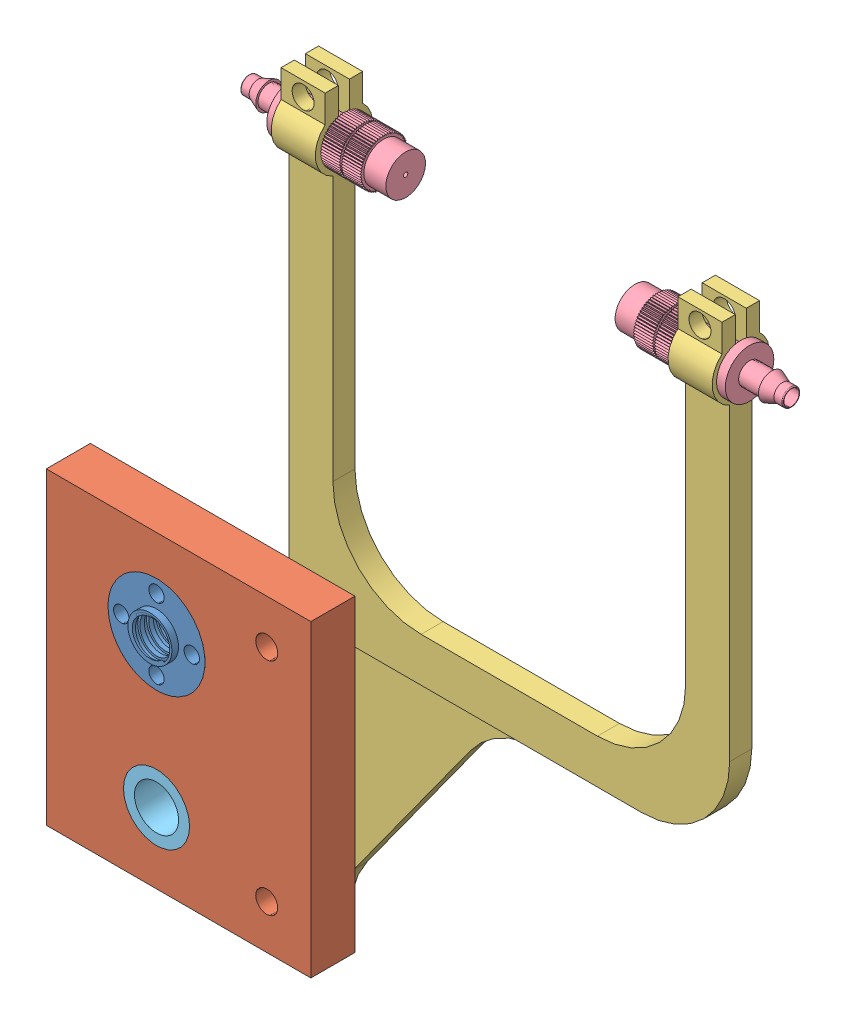
SolidWorks assembly rinser, configuration Default. Lengths in mm.
Overall size (156.5 167.17 22.24).
6 component instances, 5 part files, 11 mates.
Components (placement in the parent):
- 8mm slider-1: 8mm slider [Default] at (33.5116 -43.1967 -70.809) size (22 22 16.69)
- bearing block-1: bearing block [Default] at (33.5116 -43.1967 -77.809) size (60 70 10)
- nozzle holder-1: nozzle holder [Default] at (42.1087 -41.0385 -77.809) x (-1 0 0) z (0 0 -1) size (100 167.17 13)
- nozzle-1: nozzle [Default] at (37.0116 77.8033 -80.309) x (0 -0.928234 -0.371996) z (1 0 0) size (11 11 35.5)
- nozzle-2: nozzle [Default] at (160.0116 77.8033 -80.309) x (0 0.00294 0.999996) z (-1 0 0) size (11 11 35.5)
- linear slider-1: linear slider [Default] at (28.5116 -62.1967 -77.809) size (15 15 10)
Mates (geometry in assembly coordinates):
- Concentric1: concentric: cylinder of 8mm slider-1 through (28.5116 -28.1967 -67.809) axis (0 0 -1) radius 11; cylinder of bearing block-1 through (28.5116 -28.1967 -67.809) axis (0 0 -1) radius 11
- Coincident1: coincident: plane of 8mm slider-1 through (28.5116 -28.1967 -67.809) normal (0 0 1); plane of bearing block-1 through (33.5116 -43.1967 -67.809) normal (0 0 1)
- Coincident2: coincident: plane of bearing block-1 through (33.5116 -43.1967 -77.809) normal (0 0 -1); plane of nozzle holder-1 through (42.1087 -41.0385 -77.809) normal (0 0 1)
- Coincident3: coincident: circle of bearing block-1; circle of nozzle holder-1
- Coincident4: coincident: circle of bearing block-1; circle of nozzle holder-1
- Concentric5: concentric: cylinder of bearing block-1 through (28.5116 -62.1967 -67.809) axis (0 0 -1) radius 7.5; cylinder of linear slider-1 through (28.5116 -62.1967 -67.809) axis (0 0 -1) radius 7.5
- Coincident8: coincident: plane of bearing block-1 through (33.5116 -43.1967 -67.809) normal (0 0 1); plane of linear slider-1 through (28.5116 -62.1967 -67.809) normal (0 0 1)
- Concentric6: concentric: cylinder of nozzle holder-1 through (58.5116 77.8033 -80.309) axis (-1 0 0) radius 4; cylinder of nozzle-1 through (58.5116 77.8033 -80.309) axis (-1 0 0) radius 4
- Concentric7: concentric: cylinder of nozzle holder-1 through (138.5116 77.8033 -80.309) axis (1 0 0) radius 4; cylinder of nozzle-2 through (138.5116 77.8033 -80.309) axis (1 0 0) radius 4
- Coincident9: coincident: line of nozzle holder-1 through (148.5116 88.9713 -84.559) axis (0 -1 0); plane of nozzle-2 through (148.5116 77.8033 -80.309) normal (-1 0 0)
- Coincident10: coincident: plane of nozzle holder-1 through (48.5116 -8.1967 -82.809) normal (-1 0 0); plane of nozzle-1 through (48.5116 77.8033 -80.309) normal (1 0 0)
